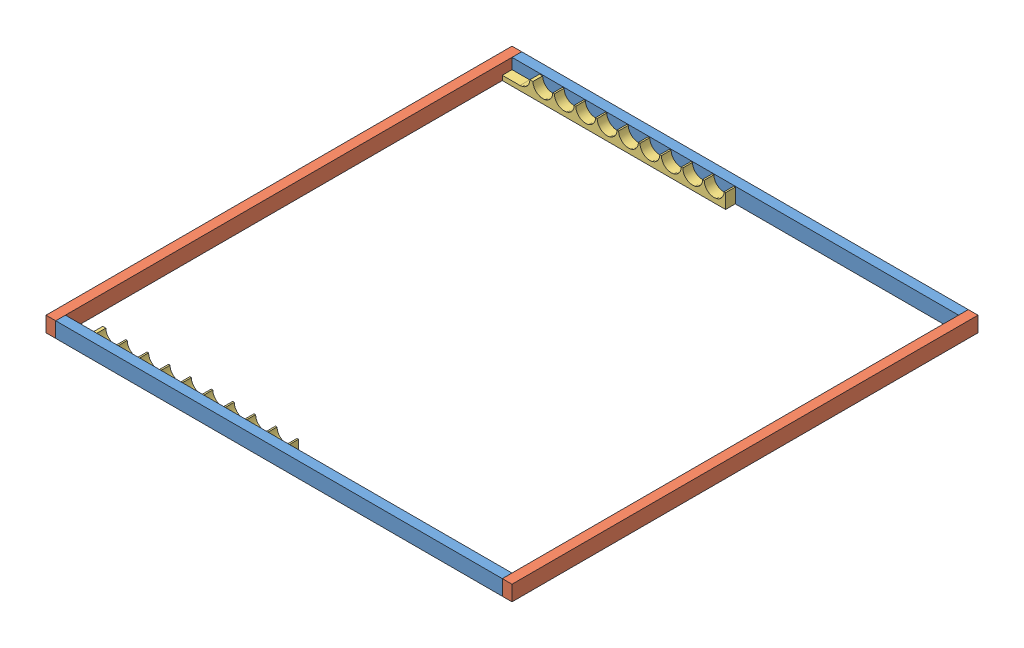
SolidWorks assembly Frame_Subassm, configuration Default. Lengths in mm.
Overall size (304.8 10 304.8).
6 component instances, 3 part files, 6 mates.
Components (placement in the parent):
- DepthFrame-1: DepthFrame [Default] at origin size (292.1 10 6.35)
- WidthFrame-2: WidthFrame [Default] at (146.05 0 -146.05) x (0 0 1) z (0 1 0) size (304.8 6.35 10)
- DepthFrame-2: DepthFrame [Default] at (0 0 -298.45) size (292.1 10 6.35)
- WidthFrame-3: WidthFrame [Default] at (-146.05 0 -146.05) x (0 0 1) z (0 -1 0) size (304.8 6.35 10)
- Slots-1: Slots [Default] at (-146.05 -5 -6.35) size (146.05 6 6.35)
- Slots-2: Slots [Default] at (-146.05 -5 -292.1) size (146.05 6 6.35)
Mates (geometry in assembly coordinates):
- Coincident2: coincident anti-aligned: line of DepthFrame-1 through (146.05 -5 6.35) axis (0 1 0); line of WidthFrame-2 through (146.05 5 6.35) axis (0 -1 0)
- Coincident3: coincident anti-aligned: plane of DepthFrame-1 through (146.05 -5 6.35) normal (1 0 0); plane of WidthFrame-2 through (146.05 0 -146.05) normal (-1 0 0)
- Coincident4: coincident anti-aligned: line of DepthFrame-1 through (146.05 5 6.35) axis (0 0 -1); line of WidthFrame-2 through (146.05 5 -298.45) axis (0 0 1)
- Coincident5: coincident anti-aligned: plane of DepthFrame-1 through (0 0 0) normal (0 0 -1); plane of Slots-1 through (-6.3 0 0) normal (0 0 1)
- Coincident6: coincident aligned: plane of DepthFrame-1 through (-146.05 -5 6.35) normal (0 -1 0); plane of Slots-1 through (-146.05 -5 0) normal (0 -1 0)
- Coincident7: coincident anti-aligned: plane of WidthFrame-3 through (-146.05 0 -146.05) normal (1 0 0); plane of Slots-1 through (-146.05 -3.2987 0) normal (-1 0 0)
